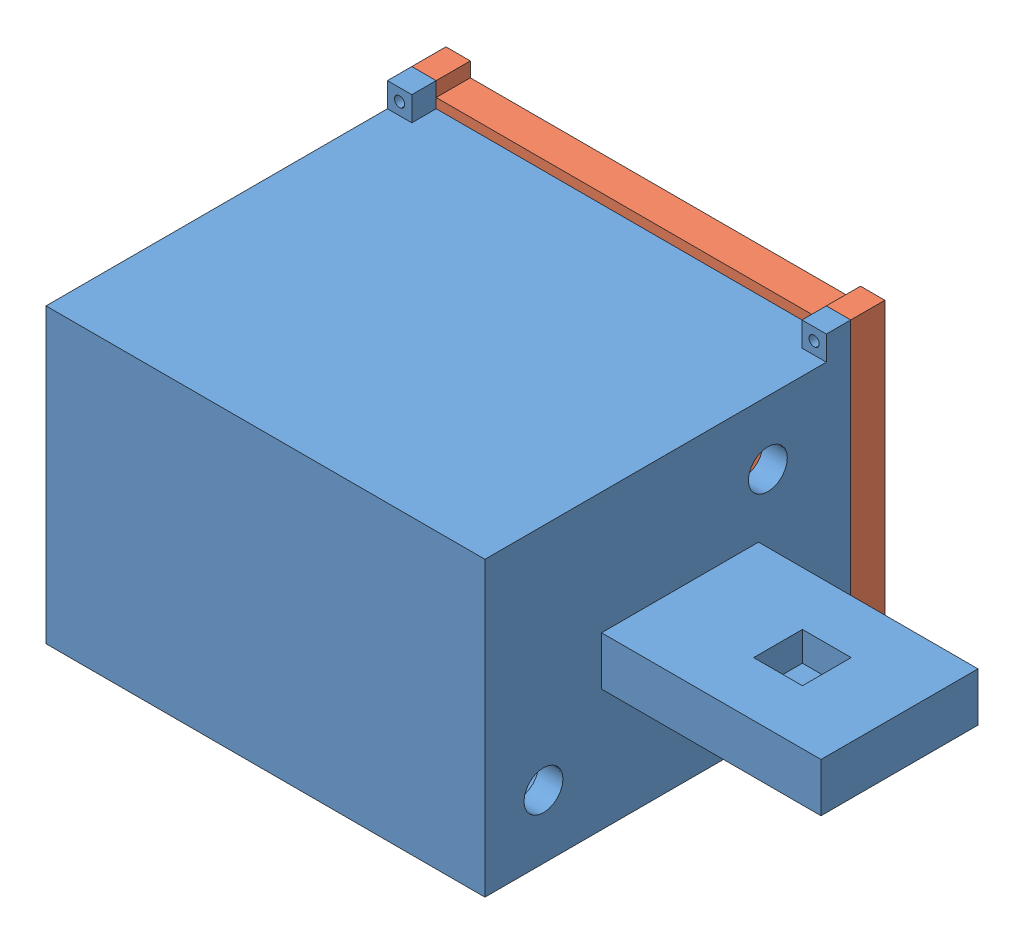
SolidWorks assembly 組合件4, configuration 預設. Lengths in mm.
Overall size (146.5 70 82).
2 component instances, 2 part files, 3 mates.
Components (placement in the parent):
- 7_20fishbody_vertical_4-1: 7_20fishbody_vertical_4 [預設] at (9.7344 8.035 109.0018) size (146.5 70 75)
- fish_lid_vertical4-3: fish_lid_vertical4 [預設] at (18.3122 -4.3565 99.0018) size (90 70 7)
Mates (geometry in assembly coordinates):
- 同軸心5: concentric: cylinder of 7_20fishbody_vertical_4-1 through (-63.2745 36.1249 114.0018) axis (0 0 -1) radius 1.05; cylinder of fish_lid_vertical4-3 through (-63.2745 36.1249 138.5836) axis (0 0 -1) radius 1.05
- 同軸心6: concentric: cylinder of 7_20fishbody_vertical_4-1 through (21.7255 -28.8751 114.0018) axis (0 0 -1) radius 1.05; cylinder of fish_lid_vertical4-3 through (21.7255 -28.8751 138.5836) axis (0 0 -1) radius 1.05
- 重合/共線/共點1: coincident: plane of 7_20fishbody_vertical_4-1 through (9.7344 8.035 109.0018) normal (0 0 -1); plane of fish_lid_vertical4-3 through (18.3122 -4.3565 109.0018) normal (0 0 1)
